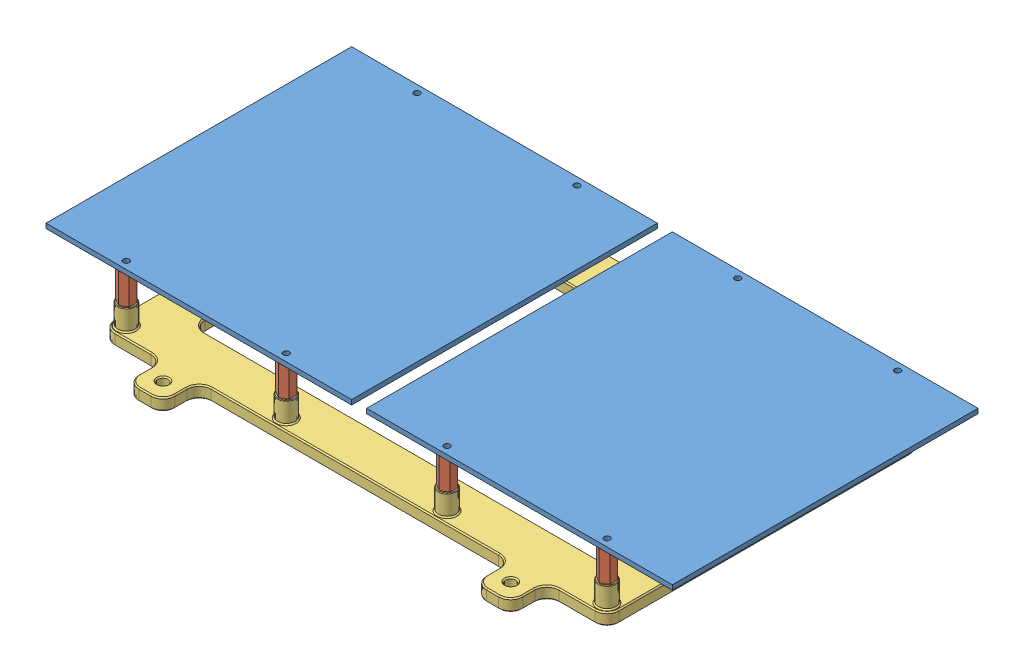
SolidWorks assembly ElectricalAssembly, configuration Default. Lengths in mm.
Overall size (208.2 22.57 128.43).
11 component instances, 3 part files, 43 mates.
Components (placement in the parent):
- PCB-1: PCB [Default] at (61.2492 100.815 -6.5236) size (101.6 1.57 101.6)
- PCB-2: PCB [Default] at (-45.3508 100.815 -6.5236) size (101.6 1.57 101.6)
- 93655A096_Male-Female Threaded Hex Standoff-1: 93655A096_Male-Female Threaded Hex Standoff [93655A096] at (-71.9383 93.865 -54.8236) x (0 -1 0) z (-1 0 0) size (14.19 5.2 4.5)
- 93655A096_Male-Female Threaded Hex Standoff-3: 93655A096_Male-Female Threaded Hex Standoff [93655A096] at (-18.7633 93.865 -54.8236) x (0 -1 0) z (-1 0 0) size (14.19 5.2 4.5)
- 93655A096_Male-Female Threaded Hex Standoff-4: 93655A096_Male-Female Threaded Hex Standoff [93655A096] at (-71.9383 93.865 41.7764) x (0 -1 0) z (-1 0 0) size (14.19 5.2 4.5)
- 93655A096_Male-Female Threaded Hex Standoff-5: 93655A096_Male-Female Threaded Hex Standoff [93655A096] at (87.8367 93.865 41.7764) x (0 -1 0) z (-1 0 0) size (14.19 5.2 4.5)
- 93655A096_Male-Female Threaded Hex Standoff-6: 93655A096_Male-Female Threaded Hex Standoff [93655A096] at (-18.7633 93.865 41.7764) x (0 -1 0) z (-1 0 0) size (14.19 5.2 4.5)
- 93655A096_Male-Female Threaded Hex Standoff-7: 93655A096_Male-Female Threaded Hex Standoff [93655A096] at (34.6617 93.865 41.7764) x (0 -1 0) z (-1 0 0) size (14.19 5.2 4.5)
- 93655A096_Male-Female Threaded Hex Standoff-8: 93655A096_Male-Female Threaded Hex Standoff [93655A096] at (34.6617 93.865 -54.8236) x (0 -1 0) z (-1 0 0) size (14.19 5.2 4.5)
- 93655A096_Male-Female Threaded Hex Standoff-9: 93655A096_Male-Female Threaded Hex Standoff [93655A096] at (87.8367 93.865 -54.8236) x (0 -1 0) z (-1 0 0) size (14.19 5.2 4.5)
- ElectricalBoard_V2-1: ElectricalBoard_V2 [Default] at (0 83.815 0) x (-1 0 0) z (0 -1 0) size (167.6 128.43 11)
Mates (geometry in assembly coordinates):
- Coincident2: coincident aligned: line of PCB-1 through (10.4492 102.385 44.2764) axis (1 0 0); line of PCB-2 through (-96.1508 102.385 44.2764) axis (1 0 0)
- Coincident3: coincident aligned: line of PCB-1 through (112.0492 102.385 -57.3236) axis (-1 0 0); line of PCB-2 through (5.4492 102.385 -57.3236) axis (-1 0 0)
- Distance1: distance = 5 mm anti-aligned: plane of PCB-2 through (5.4492 102.385 44.2764) normal (1 0 0); plane of PCB-1 through (10.4492 102.385 44.2764) normal (-1 0 0)
- Coincident5: coincident anti-aligned: plane of PCB-2 through (-45.3508 100.815 -6.5236) normal (0 -1 0); plane of 93655A096_Male-Female Threaded Hex Standoff-1 through (-71.9383 100.815 -52.2255) normal (0 1 0)
- Concentric1: concentric aligned: circle of PCB-2; circle of 93655A096_Male-Female Threaded Hex Standoff-1
- Coincident6: coincident anti-aligned: plane of PCB-2 through (-45.3508 100.815 -6.5236) normal (0 -1 0); plane of 93655A096_Male-Female Threaded Hex Standoff-6 through (-18.7633 100.815 44.3745) normal (0 1 0)
- Coincident7: coincident anti-aligned: plane of PCB-2 through (-45.3508 100.815 -6.5236) normal (0 -1 0); plane of 93655A096_Male-Female Threaded Hex Standoff-3 through (-18.7633 100.815 -52.2255) normal (0 1 0)
- Coincident8: coincident anti-aligned: plane of PCB-2 through (-45.3508 100.815 -6.5236) normal (0 -1 0); plane of 93655A096_Male-Female Threaded Hex Standoff-4 through (-71.9383 100.815 44.3745) normal (0 1 0)
- Coincident9: coincident anti-aligned: plane of PCB-1 through (61.2492 100.815 -6.5236) normal (0 -1 0); plane of 93655A096_Male-Female Threaded Hex Standoff-5 through (87.8367 100.815 44.3745) normal (0 1 0)
- Coincident10: coincident anti-aligned: plane of PCB-1 through (61.2492 100.815 -6.5236) normal (0 -1 0); plane of 93655A096_Male-Female Threaded Hex Standoff-7 through (34.6617 100.815 44.3745) normal (0 1 0)
- Coincident11: coincident anti-aligned: plane of PCB-1 through (61.2492 100.815 -6.5236) normal (0 -1 0); plane of 93655A096_Male-Female Threaded Hex Standoff-9 through (87.8367 100.815 -52.2255) normal (0 1 0)
- Coincident12: coincident anti-aligned: plane of PCB-1 through (61.2492 100.815 -6.5236) normal (0 -1 0); plane of 93655A096_Male-Female Threaded Hex Standoff-8 through (34.6617 100.815 -52.2255) normal (0 1 0)
- Concentric2: concentric aligned: circle of PCB-2; circle of 93655A096_Male-Female Threaded Hex Standoff-3
- Concentric3: concentric aligned: circle of PCB-2; circle of 93655A096_Male-Female Threaded Hex Standoff-4
- Concentric4: concentric aligned: circle of PCB-2; circle of 93655A096_Male-Female Threaded Hex Standoff-6
- Concentric5: concentric aligned: circle of PCB-1; circle of 93655A096_Male-Female Threaded Hex Standoff-8
- Concentric6: concentric aligned: circle of PCB-1; circle of 93655A096_Male-Female Threaded Hex Standoff-9
- Concentric7: concentric aligned: circle of PCB-1; circle of 93655A096_Male-Female Threaded Hex Standoff-5
- Concentric8: concentric aligned: circle of PCB-1; circle of 93655A096_Male-Female Threaded Hex Standoff-7
- InPlace1: in place: plane of ? through (0 90.815 0) normal (0 -1 0); moOrthogonalPlaneRef_w of ? through (0 90.815 0) normal (0 0 -1); plane of ? through (0 90.815 0) normal (-1 0 0); unknown of ?
- Coincident13: coincident aligned: 
- Coincident14: coincident aligned: plane of Part3^ElectricalBoard-1 through (0 90.815 0) normal (0 0 -1)
- Coincident15: coincident anti-aligned: plane of Part3^ElectricalBoard-1 through (0 90.815 0) normal (-1 0 0)
- InPlace2: in place: plane of ? through (0 90.815 0) normal (0 -1 0); plane of ? through (0 90.815 0) normal (0 0 -1); plane of ? through (0 90.815 0) normal (-1 0 0); unknown of ?
- Coincident16: coincident aligned: 
- Coincident17: coincident aligned: plane of Part4^ElectricalBoard-1 through (0 90.815 0) normal (0 0 -1)
- Coincident18: coincident anti-aligned: plane of Part4^ElectricalBoard-1 through (0 90.815 0) normal (-1 0 0)
- InPlace3: in place: plane of ? through (0 90.815 0) normal (0 -1 0); plane of ? through (0 90.815 0) normal (0 0 -1); plane of ? through (0 90.815 0) normal (-1 0 0); unknown of ?
- Coincident19: coincident aligned: 
- Coincident20: coincident aligned: plane of Part5^ElectricalBoard-1 through (0 90.815 0) normal (0 0 -1)
- Coincident21: coincident anti-aligned: plane of Part5^ElectricalBoard-1 through (0 90.815 0) normal (-1 0 0)
- InPlace4: in place: plane of ? through (0 90.815 0) normal (0 -1 0); plane of ? through (0 90.815 0) normal (0 0 -1); plane of ? through (0 90.815 0) normal (-1 0 0); unknown of ?
- Coincident22: coincident aligned: 
- Coincident23: coincident aligned: plane of Part6^ElectricalBoard-1 through (0 90.815 0) normal (0 0 -1)
- Coincident24: coincident anti-aligned: plane of Part6^ElectricalBoard-1 through (0 90.815 0) normal (-1 0 0)
- InPlace5: in place: plane of ? through (0 85.815 0) normal (0 -1 0); plane of ? through (0 85.815 0) normal (0 0 -1); plane of ? through (0 85.815 0) normal (-1 0 0); unknown of ?
- Coincident13: coincident aligned: 
- Coincident14: coincident aligned: plane of Part1^ElectricalBoard-1 through (0 85.815 0) normal (0 0 -1)
- Coincident15: coincident anti-aligned: plane of Part1^ElectricalBoard-1 through (0 85.815 0) normal (-1 0 0)
- InPlace6: in place: plane of ? through (0 85.815 0) normal (0 -1 0); plane of ? through (0 85.815 0) normal (0 0 -1); plane of ? through (0 85.815 0) normal (-1 0 0); unknown of ElectricalBoard_V2-1
- Coincident16: coincident aligned: 
- Coincident17: coincident aligned: plane of ElectricalBoard_V2-1 through (0 83.815 0) normal (0 0 -1)
- Coincident18: coincident anti-aligned: plane of ElectricalBoard_V2-1 through (0 83.815 0) normal (-1 0 0)
